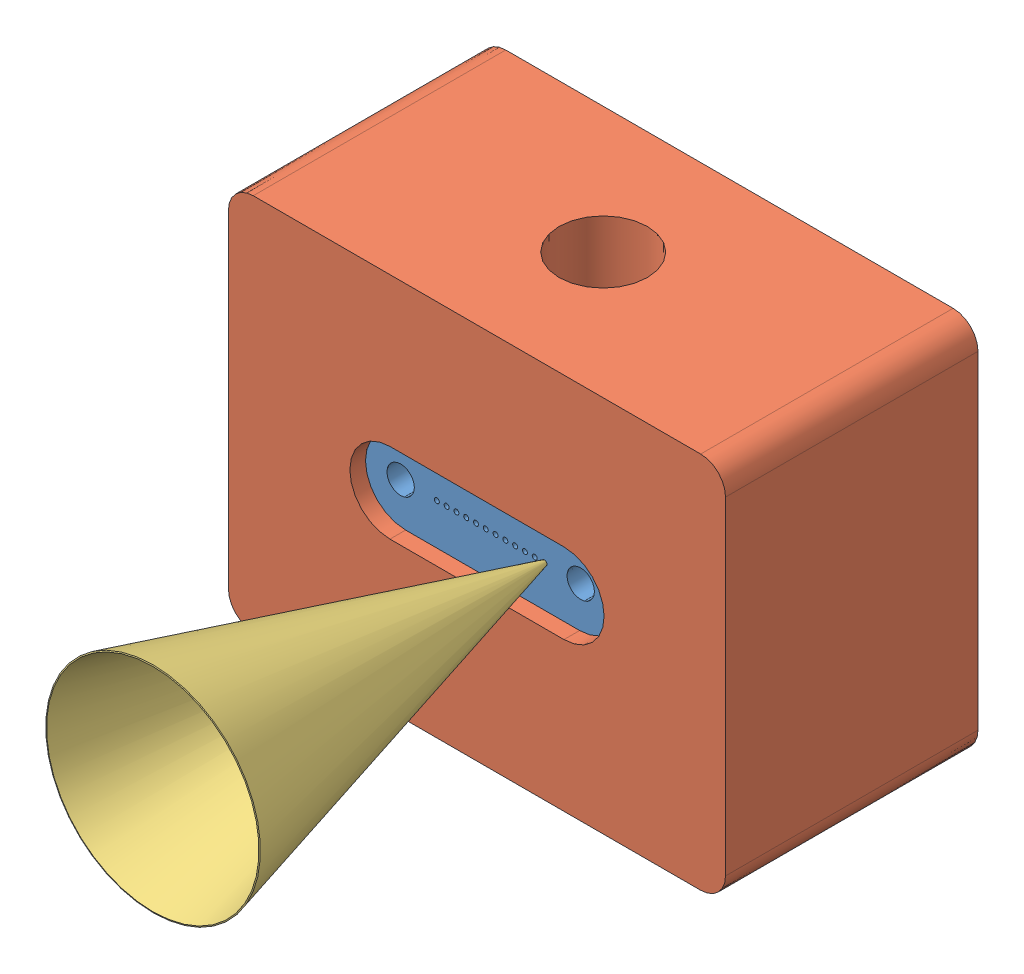
SolidWorks assembly Ferrule Holder Final, configuration Default. Lengths in mm.
Overall size (12.7 9.65 18.01).
3 component instances, 3 part files, 4 mates.
Components (placement in the parent):
- Ferrule_Old-1: Ferrule_Old [Default] at (2.4779 4.9646 1.8723) size (7 3 8)
- Ferrule Holder Final-2: Ferrule Holder Final [Default] at (8.8779 9.7656 10.2723) x (-1 0 0) z (0 0 1) size (12.7 9.65 6.45)
- Interference Cone-1: Interference Cone [Default] at (3.8529 4.9646 9.8723) x (1 0 0) z (0 -1 0) size (5.49 10.01 5.49)
Mates (geometry in assembly coordinates):
- Coincident1: coincident anti-aligned: plane of Ferrule_Old-1 through (-0.7221 6.2146 1.8723) normal (0 1 0); plane of Ferrule Holder Final-2 through (-0.9721 6.2146 23.3723) normal (0 -1 0)
- Coincident2: coincident anti-aligned: plane of Ferrule_Old-1 through (2.4779 4.9646 9.8723) normal (0 0 1); plane of Ferrule Holder Final-2 through (8.8779 0.1136 9.8723) normal (0 0 -1)
- Distance2: distance = 0.25 mm anti-aligned: plane of Ferrule Holder Final-2 through (-0.9721 6.2146 23.3723) normal (1 0 0); plane of Ferrule_Old-1 through (-0.7221 3.7146 1.8723) normal (-1 0 0)
- Coincident4: coincident aligned: circle of Ferrule_Old-1; circle of Interference Cone-1
